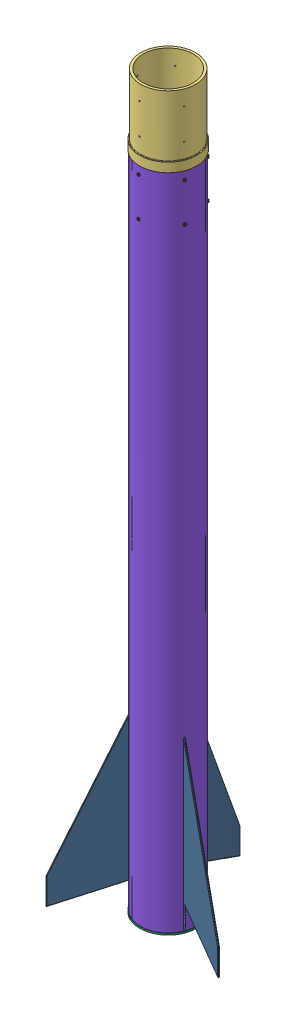
SolidWorks assembly FinalMotorAssembly, configuration Default. Lengths in mm.
Overall size (309.6 1522.27 293.77).
26 component instances, 11 part files, 53 mates.
Components (placement in the parent):
- NFPAMotor-1: NFPAMotor [Default] at (441.9192 62.775 1014.1929) size (101.6 1308.35 101.6)
- NFPA_ThrustPlate_MotorTube_V1-1: NFPA_ThrustPlate_MotorTube_V1 [Default] at (441.9192 1358.429 1014.1929) x (0 1 0) z (-0.351709 0 0.936109) size (9.95 104.2 104.2)
- NFPA_MotorCoupler_MotorTube_V1-1: NFPA_MotorCoupler_MotorTube_V1 [Default] at (441.9192 1292.229 1014.1929) x (0 -1 0) z (-0.351709 0 0.936109) size (273.05 118.8 118.8)
- 3014T471_STEEL EYEBOLT WITH SHOULDER - FOR LIFTING-1: 3014T471_STEEL EYEBOLT WITH SHOULDER - FOR LIFTING [3014T471] at (441.9192 1401.7508 1014.1929) x (0.022194 0 0.999754) z (-0.999754 0 0.022194) size (42.07 88.72 17.46)
- NFPA_LowerRetainingStructure_V1-1: NFPA_LowerRetainingStructure_V1 [Default] at (441.9192 49.059 1014.1929) x (0 -1 0) z (-0.388228 0 0.921563) size (26.42 114.6 114.6)
- NFPA_LowerRetainingStructurePlate_MotorTube_V1-1: NFPA_LowerRetainingStructurePlate_MotorTube_V1 [Default] at (441.9192 45.884 1014.1929) x (0.921563 0 0.388228) z (-0.388228 0 0.921563) size (118.62 3.17 118.62)
- 91253A003_ALLOY STEEL FLAT-HEAD SOCKET CAP SCREW-1: 91253A003_ALLOY STEEL FLAT-HEAD SOCKET CAP SCREW [91253A003] at (421.6287 1363.429 1068.1981) x (0.936109 0 0.351709) z (-0.351709 0 0.936109) size (10.44 10.44 25.68)
- 91253A003_ALLOY STEEL FLAT-HEAD SOCKET CAP SCREW-2: 91253A003_ALLOY STEEL FLAT-HEAD SOCKET CAP SCREW [91253A003] at (495.9244 1363.429 1034.4834) x (0.351709 0 -0.936109) z (0.936109 0 0.351709) size (10.44 10.44 25.68)
- 91253A003_ALLOY STEEL FLAT-HEAD SOCKET CAP SCREW-4: 91253A003_ALLOY STEEL FLAT-HEAD SOCKET CAP SCREW [91253A003] at (387.914 1363.429 993.9024) x (-0.351709 0 0.936109) z (-0.936109 0 -0.351709) size (10.44 10.44 25.68)
- 91253A003_ALLOY STEEL FLAT-HEAD SOCKET CAP SCREW-5: 91253A003_ALLOY STEEL FLAT-HEAD SOCKET CAP SCREW [91253A003] at (462.2097 1363.429 960.1877) x (-0.936109 0 -0.351709) z (0.351709 0 -0.936109) size (10.44 10.44 25.68)
- NFPA_CarbonTube_MotorTube_V1-1: NFPA_CarbonTube_MotorTube_V1 [Default] at (441.9192 49.0516 1014.1929) x (0.936109 0 0.351709) z (-0.351709 0 0.936109) size (116.6 1370.17 116.6)
- 93615A211_TYPE 18-8 SS LOW PROFILE SOCKET CAP SCREW-2: 93615A211_TYPE 18-8 SS LOW PROFILE SOCKET CAP SCREW [93615A211] at (473.3337 1402.229 974.8291) x (0.625654 0.599374 0.499308) z (-0.623769 0 0.781609) size (6.35 6.35 10.55)
- 93615A211_TYPE 18-8 SS LOW PROFILE SOCKET CAP SCREW-3: 93615A211_TYPE 18-8 SS LOW PROFILE SOCKET CAP SCREW [93615A211] at (473.3337 1322.229 974.8291) x (0.781609 -0.000089 0.623769) z (-0.623769 0 0.781609) size (6.35 6.35 10.55)
- 93615A211_TYPE 18-8 SS LOW PROFILE SOCKET CAP SCREW-4: 93615A211_TYPE 18-8 SS LOW PROFILE SOCKET CAP SCREW [93615A211] at (489.064 1322.229 1031.9058) x (-0.351709 0 0.936109) z (-0.936109 0 -0.351709) size (6.35 6.35 10.55)
- 93615A211_TYPE 18-8 SS LOW PROFILE SOCKET CAP SCREW-5: 93615A211_TYPE 18-8 SS LOW PROFILE SOCKET CAP SCREW [93615A211] at (489.064 1402.229 1031.9058) x (-0.327565 0.36412 0.871847) z (-0.936109 0 -0.351709) size (6.35 6.35 10.55)
- 93615A211_TYPE 18-8 SS LOW PROFILE SOCKET CAP SCREW-6: 93615A211_TYPE 18-8 SS LOW PROFILE SOCKET CAP SCREW [93615A211] at (439.6417 1322.229 1064.5038) x (-0.998977 0 -0.045222) z (0.045222 0 -0.998977) size (6.35 6.35 10.55)
- 93615A211_TYPE 18-8 SS LOW PROFILE SOCKET CAP SCREW-7: 93615A211_TYPE 18-8 SS LOW PROFILE SOCKET CAP SCREW [93615A211] at (439.6417 1402.229 1064.5038) x (-0.998977 0 -0.045222) z (0.045222 0 -0.998977) size (6.35 6.35 10.55)
- 93615A211_TYPE 18-8 SS LOW PROFILE SOCKET CAP SCREW-8: 93615A211_TYPE 18-8 SS LOW PROFILE SOCKET CAP SCREW [93615A211] at (393.3668 1402.229 1027.5738) x (-0.265692 0 -0.964058) z (0.964058 0 -0.265692) size (6.35 6.35 10.55)
- 93615A211_TYPE 18-8 SS LOW PROFILE SOCKET CAP SCREW-9: 93615A211_TYPE 18-8 SS LOW PROFILE SOCKET CAP SCREW [93615A211] at (393.3668 1322.229 1027.5738) x (-0.265692 0 -0.964058) z (0.964058 0 -0.265692) size (6.35 6.35 10.55)
- 93615A211_TYPE 18-8 SS LOW PROFILE SOCKET CAP SCREW-10: 93615A211_TYPE 18-8 SS LOW PROFILE SOCKET CAP SCREW [93615A211] at (414.1896 1322.229 972.1518) x (0.83477 0 -0.550599) z (0.550599 0 0.83477) size (6.35 6.35 10.55)
- 93615A211_TYPE 18-8 SS LOW PROFILE SOCKET CAP SCREW-11: 93615A211_TYPE 18-8 SS LOW PROFILE SOCKET CAP SCREW [93615A211] at (414.1896 1402.229 972.1518) x (0.83477 0 -0.550599) z (0.550599 0 0.83477) size (6.35 6.35 10.55)
- Fins-2: Fins [Default] at (442.2659 2759.0055 1011.9666) x (-0.772644 0 0.63484) z (0.63484 0 0.772644) size (128.37 356.05 3)
- Fins-3: Fins [Default] at (443.6738 2759.0055 1015.6063) x (-0.163466 0 -0.986549) z (-0.986549 0 0.163466) size (128.37 356.05 3)
- Fins-4: Fins [Default] at (439.8178 2759.0055 1015.0057) x (0.936109 0 0.351709) z (0.351709 0 -0.936109) size (128.37 356.05 3)
- NFPA_MotorRetainingRing_MotorTube_V1-1: NFPA_MotorRetainingRing_MotorTube_V1 [Default] at (441.9192 1115.8445 1014.1929) x (0.999984 0 0.005706) z (-0.005706 0 0.999984) size (114.3 12.7 114.3)
- NFPA_MotorRetainingRing_MotorTube_V1-2: NFPA_MotorRetainingRing_MotorTube_V1 [Default] at (441.9192 519.8056 1014.1929) x (0.298 0 -0.954566) z (0.954566 0 0.298) size (114.3 12.7 114.3)
Mates (geometry in assembly coordinates):
- Coincident1: coincident anti-aligned: plane of NFPAMotor-1 through (441.9192 1358.429 1014.1929) normal (0 1 0); plane of NFPA_ThrustPlate_MotorTube_V1-1 through (443.6433 1358.429 1009.6039) normal (0 -1 0)
- Concentric1: concentric anti-aligned: circle of NFPAMotor-1; circle of NFPA_ThrustPlate_MotorTube_V1-1
- Concentric2: concentric anti-aligned: circle of NFPA_ThrustPlate_MotorTube_V1-1; circle of NFPA_MotorCoupler_MotorTube_V1-1
- Concentric3: concentric aligned: circle of NFPA_ThrustPlate_MotorTube_V1-1; circle of NFPA_MotorCoupler_MotorTube_V1-1
- Concentric4: concentric aligned: circle of NFPA_ThrustPlate_MotorTube_V1-1; circle of 3014T471_STEEL EYEBOLT WITH SHOULDER - FOR LIFTING-1
- Coincident2: coincident anti-aligned: plane of NFPA_ThrustPlate_MotorTube_V1-1 through (443.6433 1366.429 1009.6039) normal (0 1 0); plane of 3014T471_STEEL EYEBOLT WITH SHOULDER - FOR LIFTING-1 through (441.7485 1366.429 1006.5053) normal (0 -1 0)
- Concentric5: concentric aligned: circle of NFPAMotor-1; circle of NFPA_LowerRetainingStructure_V1-1
- Coincident3: coincident anti-aligned: plane of NFPAMotor-1 through (441.9192 62.775 1014.1929) normal (0 1 0); plane of NFPA_LowerRetainingStructure_V1-1 through (487.4598 62.775 1033.3778) normal (0 -1 0)
- Concentric6: concentric anti-aligned: circle of NFPA_LowerRetainingStructure_V1-1; circle of NFPA_LowerRetainingStructurePlate_MotorTube_V1-1
- Concentric7: concentric anti-aligned: circle of NFPA_LowerRetainingStructure_V1-1; circle of NFPA_LowerRetainingStructurePlate_MotorTube_V1-1
- Coincident4: coincident anti-aligned: plane of NFPA_LowerRetainingStructure_V1-1 through (489.5622 49.059 1034.2636) normal (0 -1 0); plane of NFPA_LowerRetainingStructurePlate_MotorTube_V1-1 through (441.9192 49.059 1014.1929) normal (0 1 0)
- Concentric8: concentric anti-aligned: circle of NFPA_MotorCoupler_MotorTube_V1-1; circle of 91253A003_ALLOY STEEL FLAT-HEAD SOCKET CAP SCREW-1
- Coincident5: coincident aligned: cone of NFPA_MotorCoupler_MotorTube_V1-1 through (421.819 1363.429 1067.6915) axis (0.351709 0 -0.936109); cone of 91253A003_ALLOY STEEL FLAT-HEAD SOCKET CAP SCREW-1 through (422.7632 1363.429 1065.1784) axis (0.351709 0 -0.936109)
- Concentric9: concentric anti-aligned: circle of NFPA_MotorCoupler_MotorTube_V1-1; circle of 91253A003_ALLOY STEEL FLAT-HEAD SOCKET CAP SCREW-2
- Coincident6: coincident aligned: cone of NFPA_MotorCoupler_MotorTube_V1-1 through (495.4178 1363.429 1034.2931) axis (-0.936109 0 -0.351709); cone of 91253A003_ALLOY STEEL FLAT-HEAD SOCKET CAP SCREW-2 through (492.9047 1363.429 1033.3488) axis (-0.936109 0 -0.351709)
- Concentric10: concentric anti-aligned: circle of NFPA_MotorCoupler_MotorTube_V1-1; circle of 91253A003_ALLOY STEEL FLAT-HEAD SOCKET CAP SCREW-4
- Coincident7: coincident aligned: cone of NFPA_MotorCoupler_MotorTube_V1-1 through (388.4205 1363.429 994.0927) axis (0.936109 0 0.351709); cone of 91253A003_ALLOY STEEL FLAT-HEAD SOCKET CAP SCREW-4 through (390.9337 1363.429 995.0369) axis (0.936109 0 0.351709)
- Concentric11: concentric anti-aligned: circle of NFPA_MotorCoupler_MotorTube_V1-1; circle of 91253A003_ALLOY STEEL FLAT-HEAD SOCKET CAP SCREW-5
- Coincident8: coincident aligned: cone of NFPA_MotorCoupler_MotorTube_V1-1 through (462.0193 1363.429 960.6942) axis (-0.351709 0 0.936109); cone of 91253A003_ALLOY STEEL FLAT-HEAD SOCKET CAP SCREW-5 through (461.0751 1363.429 963.2074) axis (-0.351709 0 0.936109)
- Concentric12: concentric aligned: cylinder of NFPA_MotorCoupler_MotorTube_V1-1 through (439.3347 1402.229 1071.2844) axis (-0.045222 0 0.998977) radius 1.3526; cylinder of NFPA_CarbonTube_MotorTube_V1-1 through (439.2827 1402.229 1072.4332) axis (-0.045222 0 0.998977) radius 2.5908
- Concentric13: concentric aligned: cylinder of NFPA_MotorCoupler_MotorTube_V1-1 through (495.4178 1402.229 1034.2931) axis (0.936109 0 0.351709) radius 1.3526; cylinder of NFPA_CarbonTube_MotorTube_V1-1 through (496.4943 1402.229 1034.6975) axis (0.936109 0 0.351709) radius 2.5908
- Concentric14: concentric aligned: cylinder of NFPA_MotorCoupler_MotorTube_V1-1 through (477.5676 1402.229 969.5239) axis (0.623769 0 -0.781609) radius 1.3526; cylinder of NFPA_CarbonTube_MotorTube_V1-1 through (478.2849 1402.229 968.6251) axis (0.623769 0 -0.781609) radius 2.5908
- Concentric16: concentric anti-aligned: cylinder of NFPA_MotorCoupler_MotorTube_V1-1 through (477.5676 1402.229 969.5239) axis (0.623769 0 -0.781609) radius 1.3526; cylinder of 93615A211_TYPE 18-8 SS LOW PROFILE SOCKET CAP SCREW-2 through (479.4256 1402.229 967.1957) axis (-0.623769 0 0.781609) radius 2.8702
- Tangent4: tangent anti-aligned: cylinder of NFPA_CarbonTube_MotorTube_V1-1 through (441.9192 1419.2216 1014.1929) axis (0 -1 0) radius 58.3; plane of 93615A211_TYPE 18-8 SS LOW PROFILE SOCKET CAP SCREW-2 through (478.2849 1402.229 968.6251) normal (-0.623769 0 0.781609)
- Concentric17: concentric anti-aligned: cylinder of NFPA_MotorCoupler_MotorTube_V1-1 through (477.5676 1322.229 969.5239) axis (0.623769 0 -0.781609) radius 1.3526; cylinder of 93615A211_TYPE 18-8 SS LOW PROFILE SOCKET CAP SCREW-3 through (479.4256 1322.229 967.1957) axis (-0.623769 0 0.781609) radius 2.8702
- Tangent5: tangent anti-aligned: cylinder of NFPA_CarbonTube_MotorTube_V1-1 through (441.9192 1419.2216 1014.1929) axis (0 -1 0) radius 58.3; plane of 93615A211_TYPE 18-8 SS LOW PROFILE SOCKET CAP SCREW-3 through (478.2849 1322.229 968.6251) normal (-0.623769 0 0.781609)
- Concentric20: concentric anti-aligned: cylinder of NFPA_MotorCoupler_MotorTube_V1-1 through (495.4178 1322.229 1034.2931) axis (0.936109 0 0.351709) radius 1.3526; cylinder of 93615A211_TYPE 18-8 SS LOW PROFILE SOCKET CAP SCREW-4 through (498.2063 1322.229 1035.3407) axis (-0.936109 0 -0.351709) radius 2.8702
- Tangent6: tangent anti-aligned: cylinder of NFPA_CarbonTube_MotorTube_V1-1 through (441.9192 1419.2216 1014.1929) axis (0 -1 0) radius 58.3; plane of 93615A211_TYPE 18-8 SS LOW PROFILE SOCKET CAP SCREW-4 through (496.4943 1322.229 1034.6975) normal (-0.936109 0 -0.351709)
- Concentric21: concentric anti-aligned: cylinder of NFPA_MotorCoupler_MotorTube_V1-1 through (495.4178 1402.229 1034.2931) axis (0.936109 0 0.351709) radius 1.3526; cylinder of 93615A211_TYPE 18-8 SS LOW PROFILE SOCKET CAP SCREW-5 through (498.2063 1402.229 1035.3407) axis (-0.936109 0 -0.351709) radius 2.8702
- Tangent7: tangent anti-aligned: cylinder of NFPA_CarbonTube_MotorTube_V1-1 through (441.9192 1419.2216 1014.1929) axis (0 -1 0) radius 58.3; plane of 93615A211_TYPE 18-8 SS LOW PROFILE SOCKET CAP SCREW-5 through (496.4943 1402.229 1034.6975) normal (-0.936109 0 -0.351709)
- Concentric22: concentric anti-aligned: cylinder of NFPA_MotorCoupler_MotorTube_V1-1 through (439.3347 1322.229 1071.2844) axis (-0.045222 0 0.998977) radius 1.3526; cylinder of 93615A211_TYPE 18-8 SS LOW PROFILE SOCKET CAP SCREW-6 through (439.2 1322.229 1074.2602) axis (0.045222 0 -0.998977) radius 2.8702
- Tangent8: tangent anti-aligned: cylinder of NFPA_CarbonTube_MotorTube_V1-1 through (441.9192 1419.2216 1014.1929) axis (0 -1 0) radius 58.3; plane of 93615A211_TYPE 18-8 SS LOW PROFILE SOCKET CAP SCREW-6 through (439.2827 1322.229 1072.4332) normal (0.045222 0 -0.998977)
- Concentric23: concentric anti-aligned: cylinder of NFPA_MotorCoupler_MotorTube_V1-1 through (439.3347 1402.229 1071.2844) axis (-0.045222 0 0.998977) radius 1.3526; cylinder of 93615A211_TYPE 18-8 SS LOW PROFILE SOCKET CAP SCREW-7 through (439.2 1402.229 1074.2602) axis (0.045222 0 -0.998977) radius 2.8702
- Tangent9: tangent anti-aligned: cylinder of NFPA_CarbonTube_MotorTube_V1-1 through (441.9192 1419.2216 1014.1929) axis (0 -1 0) radius 58.3; plane of 93615A211_TYPE 18-8 SS LOW PROFILE SOCKET CAP SCREW-7 through (439.2827 1402.229 1072.4332) normal (0.045222 0 -0.998977)
- Concentric24: concentric anti-aligned: cylinder of NFPA_MotorCoupler_MotorTube_V1-1 through (386.8233 1402.229 1029.3772) axis (-0.964058 0 0.265692) radius 1.3526; cylinder of 93615A211_TYPE 18-8 SS LOW PROFILE SOCKET CAP SCREW-8 through (383.9515 1402.229 1030.1686) axis (0.964058 0 -0.265692) radius 2.8702
- Tangent10: tangent anti-aligned: cylinder of NFPA_CarbonTube_MotorTube_V1-1 through (441.9192 1419.2216 1014.1929) axis (0 -1 0) radius 58.3; plane of 93615A211_TYPE 18-8 SS LOW PROFILE SOCKET CAP SCREW-8 through (385.7146 1402.229 1029.6828) normal (0.964058 0 -0.265692)
- Concentric25: concentric anti-aligned: cylinder of NFPA_MotorCoupler_MotorTube_V1-1 through (386.8233 1322.229 1029.3772) axis (-0.964058 0 0.265692) radius 1.3526; cylinder of 93615A211_TYPE 18-8 SS LOW PROFILE SOCKET CAP SCREW-9 through (383.9515 1322.229 1030.1686) axis (0.964058 0 -0.265692) radius 2.8702
- Tangent11: tangent anti-aligned: cylinder of NFPA_CarbonTube_MotorTube_V1-1 through (441.9192 1419.2216 1014.1929) axis (0 -1 0) radius 58.3; plane of 93615A211_TYPE 18-8 SS LOW PROFILE SOCKET CAP SCREW-9 through (385.7146 1322.229 1029.6828) normal (0.964058 0 -0.265692)
- Concentric26: concentric anti-aligned: cylinder of NFPA_MotorCoupler_MotorTube_V1-1 through (410.4524 1402.229 966.4858) axis (-0.550599 0 -0.83477) radius 1.3526; cylinder of 93615A211_TYPE 18-8 SS LOW PROFILE SOCKET CAP SCREW-11 through (408.8123 1402.229 963.9992) axis (0.550599 0 0.83477) radius 2.8702
- Tangent12: tangent anti-aligned: cylinder of NFPA_CarbonTube_MotorTube_V1-1 through (441.9192 1419.2216 1014.1929) axis (0 -1 0) radius 58.3; plane of 93615A211_TYPE 18-8 SS LOW PROFILE SOCKET CAP SCREW-11 through (409.8193 1402.229 965.5258) normal (0.550599 0 0.83477)
- Concentric27: concentric anti-aligned: cylinder of NFPA_MotorCoupler_MotorTube_V1-1 through (410.4524 1322.229 966.4858) axis (-0.550599 0 -0.83477) radius 1.3526; cylinder of 93615A211_TYPE 18-8 SS LOW PROFILE SOCKET CAP SCREW-10 through (408.8123 1322.229 963.9992) axis (0.550599 0 0.83477) radius 2.8702
- Tangent13: tangent anti-aligned: cylinder of NFPA_CarbonTube_MotorTube_V1-1 through (441.9192 1419.2216 1014.1929) axis (0 -1 0) radius 58.3; plane of 93615A211_TYPE 18-8 SS LOW PROFILE SOCKET CAP SCREW-10 through (409.8193 1322.229 965.5258) normal (0.550599 0 0.83477)
- Coincident9: coincident anti-aligned: plane of NFPA_CarbonTube_MotorTube_V1-1 through (405.5527 349.0516 1046.0146) normal (-0.63484 0 -0.772644); plane of Fins-2 through (444.1704 2759.0055 1014.2845) normal (0.63484 0 0.772644)
- Coincident10: coincident anti-aligned: plane of NFPA_CarbonTube_MotorTube_V1-1 through (403.6482 349.0516 1043.6967) normal (0 -1 0); plane of Fins-2 through (400.8281 349.0516 1046.0138) normal (0 1 0)
- Tangent14: tangent anti-aligned: cylinder of NFPA_CarbonTube_MotorTube_V1-1 through (441.9192 1419.2216 1014.1929) axis (0 -1 0) radius 58.3; plane of Fins-2 through (397.8263 99.0055 1052.363) normal (0.772644 0 -0.63484)
- Coincident11: coincident anti-aligned: plane of NFPA_CarbonTube_MotorTube_V1-1 through (435.5036 349.0516 966.2974) normal (-0.986549 0 0.163466); plane of Fins-3 through (443.6738 2759.0055 1015.6063) normal (0.986549 0 -0.163466)
- Coincident12: coincident anti-aligned: plane of NFPA_CarbonTube_MotorTube_V1-1 through (435.5036 349.0516 966.2974) normal (0 -1 0); plane of Fins-3 through (434.907 349.0516 962.6965) normal (0 1 0)
- Tangent15: tangent anti-aligned: cylinder of NFPA_CarbonTube_MotorTube_V1-1 through (441.9192 1419.2216 1014.1929) axis (0 -1 0) radius 58.3; plane of Fins-3 through (430.9093 99.0055 956.9223) normal (0.163466 0 0.986549)
- Coincident13: coincident anti-aligned: plane of NFPA_CarbonTube_MotorTube_V1-1 through (486.6057 349.0516 1032.5846) normal (0.351709 0 -0.936109); plane of Fins-4 through (439.8178 2759.0055 1015.0057) normal (-0.351709 0 0.936109)
- Coincident14: coincident anti-aligned: plane of NFPA_CarbonTube_MotorTube_V1-1 through (486.6057 349.0516 1032.5846) normal (0 -1 0); plane of Fins-4 through (490.0225 349.0516 1033.8683) normal (0 1 0)
- Tangent16: tangent anti-aligned: cylinder of NFPA_CarbonTube_MotorTube_V1-1 through (441.9192 1419.2216 1014.1929) axis (0 -1 0) radius 58.3; plane of Fins-4 through (497.0219 99.0055 1033.2934) normal (-0.936109 0 -0.351709)
- Concentric28: concentric anti-aligned: cylinder of NFPAMotor-1 through (441.9192 1301.279 1014.1929) axis (0 -1 0) radius 49.2125; cylinder of NFPA_MotorRetainingRing_MotorTube_V1-1 through (441.9192 1115.8445 1014.1929) axis (0 1 0) radius 49.276
- Concentric29: concentric anti-aligned: cylinder of NFPAMotor-1 through (441.9192 1301.279 1014.1929) axis (0 -1 0) radius 49.2125; cylinder of NFPA_MotorRetainingRing_MotorTube_V1-2 through (441.9192 519.8056 1014.1929) axis (0 1 0) radius 49.276
